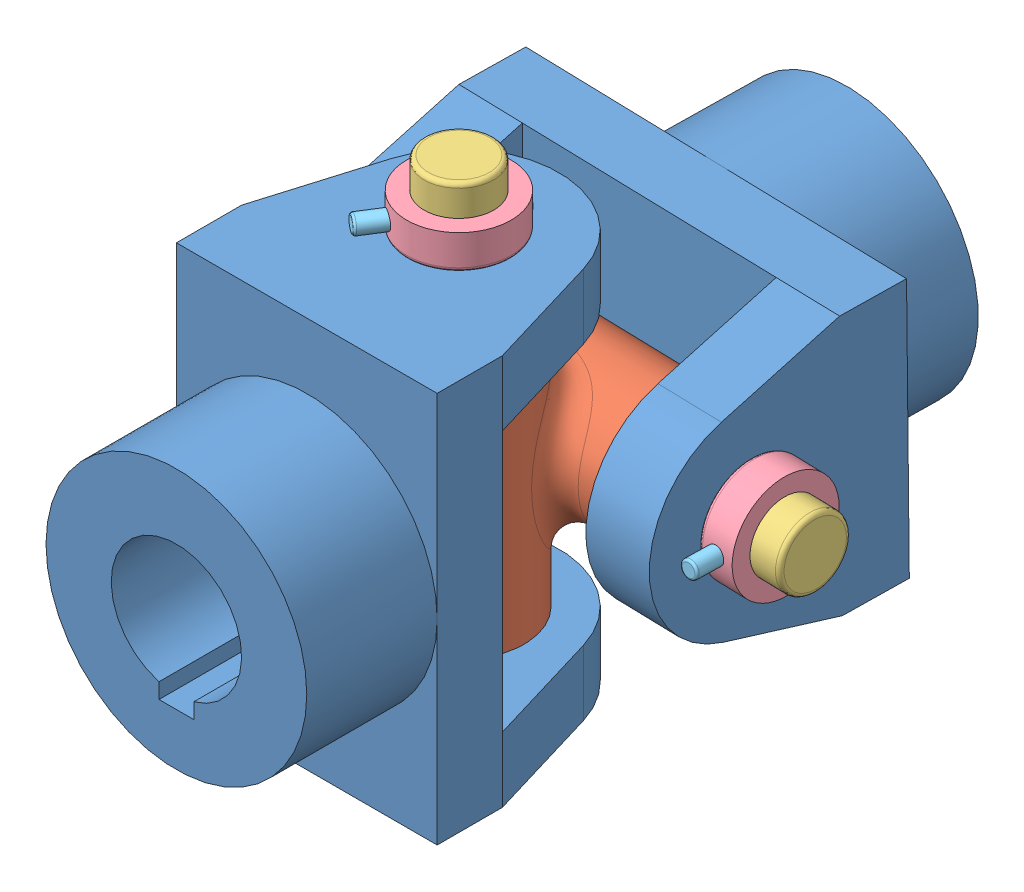
SolidWorks assembly Assem1, configuration Default. Lengths in mm.
Overall size (113.6 113 154.46).
9 component instances, 5 part files, 18 mates.
Components (placement in the parent):
- driving  Yoke-1: driving  Yoke [Default] at (82.4707 18.0755 90.865) size (60 90 88)
- 2 bearing-1: 2 bearing [Default] at (82.4707 18.0755 63.365) x (0.026396 0 -0.999652) z (0.999652 0 0.026396) size (53 60 60)
- driving  Yoke-2: driving  Yoke [Default] at (83.8037 18.3607 12.8841) x (0.000274 -0.999946 -0.010367) z (0.026395 0.010371 -0.999598) size (60 90 88)
- 3 Bolt-1: 3 Bolt [Default] at (34.0949 18.0755 39.0796) x (0.999652 0 0.026396) z (-0.026396 -0.002324 0.999649) size (113 24 24)
- 5 Bush-1: 5 Bush [Default] at (82.4707 67.0755 63.365) x (-0.845637 0 -0.533759) z (-0.533759 0 0.845637) size (24 8 24)
- 3 Bolt-4: 3 Bolt [Default] at (82.4707 -30.9245 63.365) x (0 1 0) z (-0.533759 0 0.845637) size (113 24 24)
- 5 Bush-3: 5 Bush [Default] at (132.0608 18.0755 41.6665) x (-0.000061 0.999997 0.002323) z (-0.026396 -0.002324 0.999649) size (24 8 24)
- 6 pin-1: 6 pin [Default] at (80.8694 67.0755 65.9019) x (0.82598 -0.21436 0.521351) z (-0.533759 0 0.845637) size (4 4 30)
- 6 pin-2: 6 pin [Default] at (131.9816 18.0685 44.6654) x (0.610972 -0.791523 0.014293) z (-0.026396 -0.002324 0.999649) size (4 4 30)
Mates (geometry in assembly coordinates):
- Coincident2: coincident: circle of assembly; circle of assembly; circle of driving  Yoke-1; circle of 2 bearing-1
- Coincident3: coincident: circle of assembly; circle of assembly; circle of 2 bearing-1; circle of driving  Yoke-2
- Concentric2: concentric: circle of assembly; circle of assembly; circle of driving  Yoke-2; circle of 3 Bolt-1
- Coincident4: coincident: plane of assembly; plane of assembly; plane of driving  Yoke-2 through (39.0091 48.4369 4.5103) normal (-0.999652 0 -0.026396); plane of 3 Bolt-1 through (38.0935 18.0755 39.1852) normal (0.999652 0 0.026396)
- Coincident5: coincident: circle of assembly; plane of assembly; circle of driving  Yoke-1; plane of driving  Yoke-1 through (52.4707 -26.9245 98.365) normal (0 -1 0)
- Parallel1: parallel: plane of assembly; plane of assembly; plane of driving  Yoke-1 through (52.4707 63.0755 98.365) normal (0 1 0); plane of 5 Bush-1 through (82.4707 63.0755 63.365) normal (0 -1 0)
- Concentric61: concentric: cylinder of assembly; cylinder of assembly; cylinder of 2 bearing-1 through (82.4707 48.0755 63.365) axis (0 -1 0) radius 8; cylinder of 3 Bolt-4 through (82.4707 78.0755 63.365) axis (0 -1 0) radius 8
- Coincident21: coincident: plane of assembly; plane of assembly; plane of driving  Yoke-1 through (52.4707 -26.9245 98.365) normal (0 -1 0); plane of 3 Bolt-4 through (82.4707 -26.9245 63.365) normal (0 1 0)
- Concentric7: concentric: cylinder of assembly; cylinder of assembly; cylinder of 5 Bush-1 through (82.4707 63.0755 63.365) axis (0 1 0) radius 8; cylinder of 3 Bolt-4 through (82.4707 78.0755 63.365) axis (0 -1 0) radius 8
- Coincident22: coincident: plane of assembly; plane of assembly; plane of driving  Yoke-1 through (52.4707 63.0755 98.365) normal (0 1 0); plane of 5 Bush-1 through (82.4707 63.0755 63.365) normal (0 -1 0)
- Concentric12: concentric: cylinder of assembly; cylinder of assembly; cylinder of 5 Bush-1 through (95.8147 67.0755 42.2241) axis (-0.533759 0 0.845637) radius 2; cylinder of 3 Bolt-4 through (87.8083 67.0755 54.9087) axis (-0.533759 0 0.845637) radius 2
- Concentric131: concentric: cylinder of assembly; cylinder of assembly; cylinder of 3 Bolt-1 through (143.0569 18.0755 41.9568) axis (-0.999652 0 -0.026396) radius 8; cylinder of 5 Bush-3 through (128.0621 18.0755 41.5609) axis (0.999652 0 0.026396) radius 12
- Coincident23: coincident: plane of assembly; plane of assembly; plane of driving  Yoke-2 through (128.9778 48.4369 6.886) normal (0.999652 0 0.026396); plane of 5 Bush-3 through (128.0621 18.0755 41.5609) normal (-0.999652 0 -0.026396)
- Concentric14: concentric: cylinder of assembly; cylinder of assembly; cylinder of 3 Bolt-1 through (132.3247 18.0987 31.67) axis (-0.026396 -0.002324 0.999649) radius 2; cylinder of 5 Bush-3 through (132.7207 18.1336 16.6752) axis (-0.026396 -0.002324 0.999649) radius 2
- Concentric15: concentric: cylinder of assembly; cylinder of assembly; cylinder of 3 Bolt-4 through (87.8083 67.0755 54.9087) axis (-0.533759 0 0.845637) radius 2; cylinder of 6 pin-1 through (72.8631 67.0755 78.5865) axis (0.533759 0 -0.845637) radius 2
- Tangent1: tangent: cylinder of assembly; plane of assembly; cylinder of 5 Bush-1 through (82.4707 63.0755 63.365) axis (0 1 0) radius 12; plane of 6 pin-1 through (88.8758 67.0755 53.2174) normal (0.533759 0 -0.845637)
- Concentric16: concentric: cylinder of assembly; cylinder of assembly; cylinder of 3 Bolt-1 through (132.3247 18.0987 31.67) axis (-0.026396 -0.002324 0.999649) radius 2; cylinder of 6 pin-2 through (131.5856 18.0337 59.6601) axis (0.026396 0.002324 -0.999649) radius 2
- Tangent2: tangent: cylinder of assembly; plane of assembly; cylinder of 5 Bush-3 through (128.0621 18.0755 41.5609) axis (0.999652 0 0.026396) radius 12; plane of 6 pin-2 through (132.3775 18.1034 29.6707) normal (0.026396 0.002324 -0.999649)
